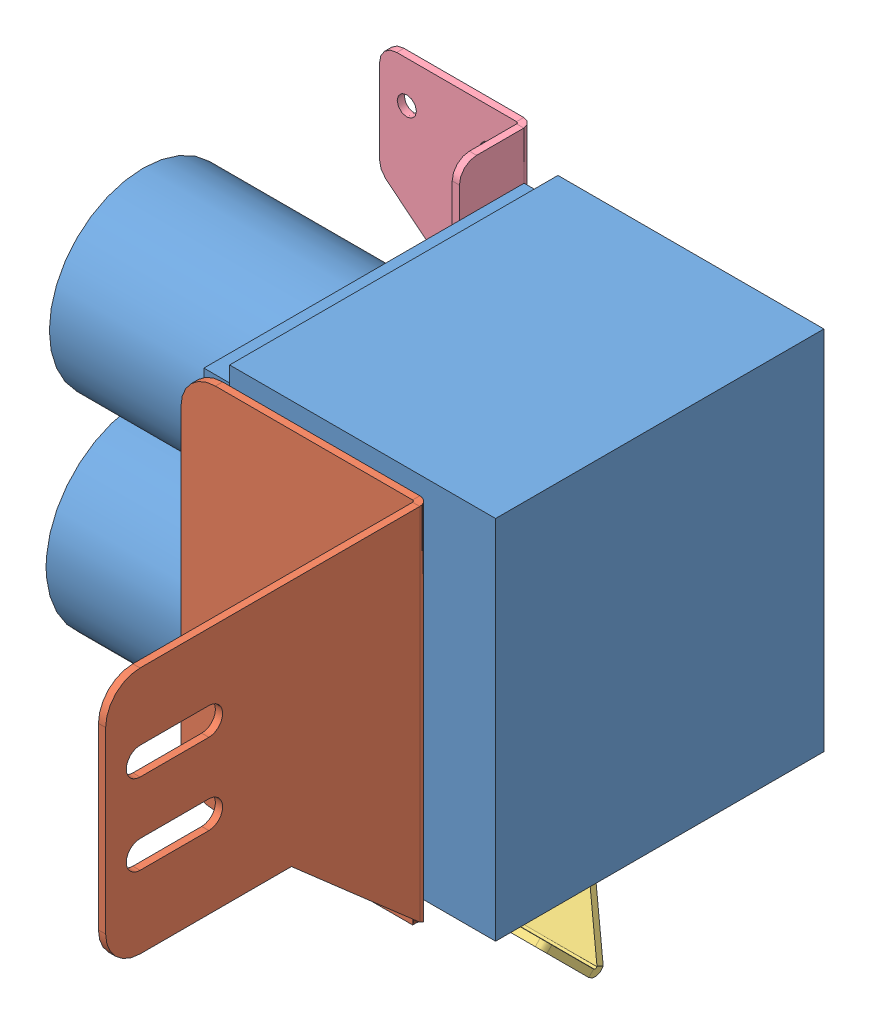
SolidWorks assembly actuator_braket_assembly, configuration Default. Lengths in mm.
Overall size (185.68 207.96 248.3).
4 component instances, 4 part files, 4 mates.
Components (placement in the parent):
- actuator_mockup-1: actuator_mockup [Default] at (10.3106 62.3956 -13.308) size (185.68 154.1 121.2)
- side_bracket-1: side_bracket [Default] at (34.8376 77.5297 101.982) x (0 0 -1) z (1 0 0) size (119.38 136.14 88.9)
- bottom_bracket-1: bottom_bracket [Default] at (2.7354 -57.0123 -15.1305) x (0 -0.707107 -0.707107) z (0 -0.707107 0.707107) size (27.62 70.03 86.18)
- reservoir_bracket-1: reservoir_bracket [Default] at (-49.7794 99.7578 -65.4145) x (0 0 -1) z (1 0 0) size (27.17 81.28 53.98)
Mates (geometry in assembly coordinates):
- Coincident2: coincident anti-aligned: plane of actuator_mockup-1 through (10.3106 62.3956 42.292) normal (0 0 1); plane of side_bracket-1 through (34.8376 77.5297 42.292) normal (0 0 -1)
- Coincident3: coincident anti-aligned: plane of actuator_mockup-1 through (-38.7794 -5.1794 -78.908) normal (0 -1 0); plane of bottom_bracket-1 through (2.7354 -5.1794 -15.1305) normal (0 1 0)
- Parallel2: parallel anti-aligned: line of actuator_mockup-1 through (-38.7794 -5.1794 -78.908) axis (1 0 0); line of bottom_bracket-1 through (-9.3296 -7.7194 -85.177) axis (-1 0 0)
- Coincident4: coincident anti-aligned: plane of actuator_mockup-1 through (-49.7794 62.3956 -13.308) normal (-1 0 0); plane of reservoir_bracket-1 through (-49.7794 85.9656 -27.0097) normal (1 0 0)
